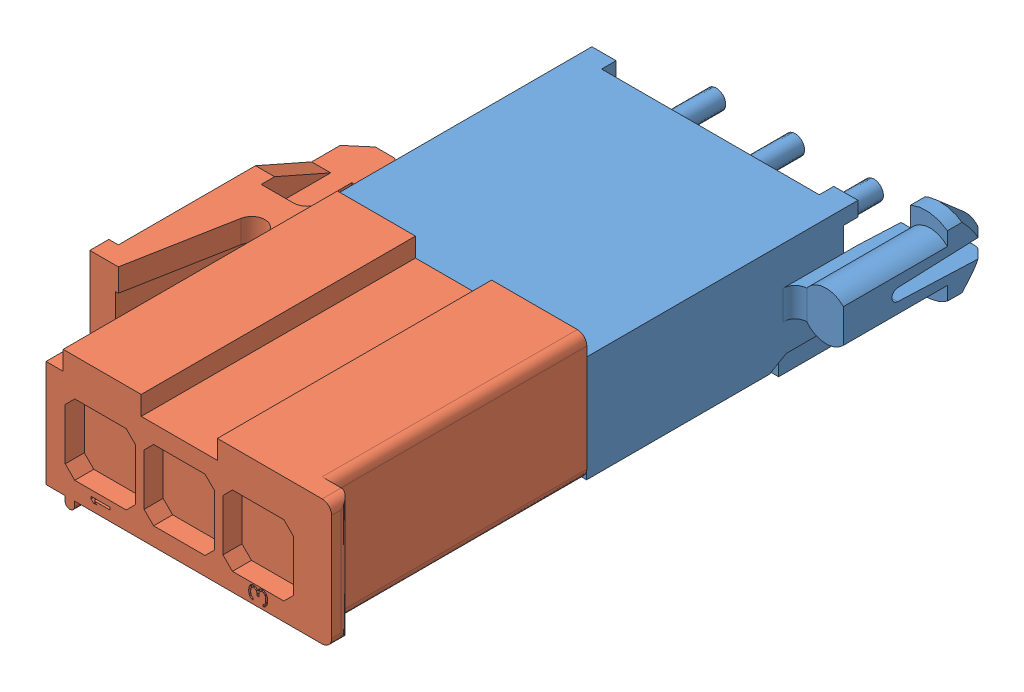
SolidWorks assembly Assem1, configuration Default. Lengths in mm.
Overall size (20.43 7.36 33).
2 component instances, 2 part files, 6 mates.
Components (placement in the parent):
- c-1-770170-0-n-3d-1: c-1-770170-0-n-3d [Default] at (-6.985 2.794 14.2494) size (17.81 6.35 18.6)
- c-172166-1-h-3d-1: c-172166-1-h-3d [Default] at (-6.985 2.794 4.9494) x (0 -1 0) z (0 0 -1) size (7.1 18.9 23.7)
Mates (geometry in assembly coordinates):
- Coincident1: coincident: line of c-1-770170-0-n-3d-1 through (1.27 0 5.588) axis (0 -1 0)
- Coincident2: coincident aligned: plane of c-1-770170-0-n-3d-1 through (0 0 14.2494) normal (1 0 0)
- Coincident3: coincident anti-aligned: plane of c-1-770170-0-n-3d-1 through (-6.985 0 14.2494) normal (0 -1 0)
- Width1: width: plane of c-1-770170-0-n-3d-1 through (-12.9032 3.5814 14.2494) normal (1 0 0); plane of c-172166-1-h-3d-1 through (-1.0668 1.016 14.2494) normal (-1 0 0); plane of c-1-770170-0-n-3d-1 through (-12.85 2.069 14.2494) normal (-1 0 0); plane of c-172166-1-h-3d-1 through (-1.12 4.519 14.2494) normal (1 0 0)
- Width2: width: plane of c-1-770170-0-n-3d-1 through (-9.3472 4.572 14.2494) normal (0 -1 0); plane of c-172166-1-h-3d-1 through (-3.6322 1.016 14.2494) normal (0 1 0); plane of c-1-770170-0-n-3d-1 through (-11.85 4.519 14.2494) normal (0 1 0); plane of c-172166-1-h-3d-1 through (-1.12 1.069 14.2494) normal (0 -1 0)
- Coincident4: coincident anti-aligned: plane of c-1-770170-0-n-3d-1 through (-13.97 0 14.2494) normal (0 0 1); plane of c-172166-1-h-3d-1 through (-13.985 6.594 14.2494) normal (0 0 -1)
